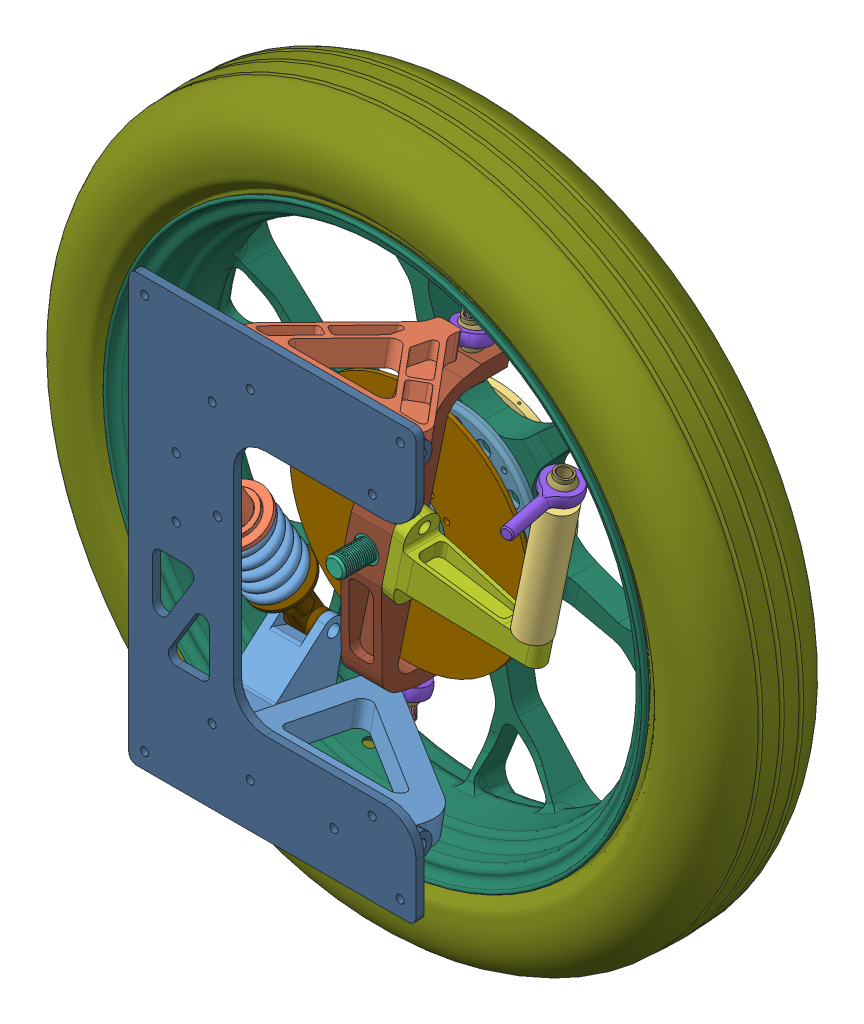
SolidWorks assembly Front Wheel Assembly, configuration Default. Lengths in mm.
Overall size (736.43 736.43 217.08).
26 component instances, 21 part files, 58 mates.
Components (placement in the parent):
- NewWishbone-1: NewWishbone [Default] at (-208.945 -92.3213 142.5637) x (1 0 0) z (0 0.196638 0.980476) size (183.89 64.96 127)
- NewWishboneTop-1: NewWishboneTop [Default] at (-199.42 176.9187 142.5637) x (1 0 0) z (0 0.196638 0.980476) size (146.05 19.05 127)
- Nut-1: Nut [Default] at (-174.02 47.8918 83.6508) x (0.981942 0.18918 0) z (0 0 1) size (130 130 15.86)
- SKF_6003-2Z.stp-1: SKF_6003-2Z.stp [Default] at (-174.02 47.8918 100.9457) x (0 0 -1) z (0.985702 -0.168499 0) size (10 35 35)
- SKF_6004-2Z.stp-1: SKF_6004-2Z.stp [Default] at (-174.02 47.8918 145.4457) x (0 0 -1) z (0.999998 -0.001926 0) size (12 42 42)
- Spindle_Light-1: Spindle_Light [Default] at (-174.0201 47.8918 152.4457) x (0 0 -1) z (0.979501 -0.20144 0) size (158.56 34 30)
- SteeringArmMount3-1: SteeringArmMount3 [Default] at (-158.1222 46.3873 152.4457) x (0 0 -1) z (0.979501 -0.20144 0) size (32.44 66.16 106.1)
- Swivel Ball Joint Rod End-1: Swivel Ball Joint Rod End [6960T231] at (-199.42 -82.9822 140.6908) x (-1 0 0) z (0 -0.980476 0.196638) size (28.57 68.26 9.89)
- BasicBrakeDisc-1: BasicBrakeDisc [Default] at (-174.02 47.8918 143.4457) x (0.999999 -0.001555 0) z (0 0 1) size (190.5 190.5 3.17)
- FrontSuspensionMountingPlate-1: FrontSuspensionMountingPlate [Default] at (-37.241 244.9178 278.0972) x (-1 0 0) z (0 0 -1) size (228.6 339.73 31.75)
- FrontSpindle-2: FrontSpindle [Default] at (-174.0201 47.8918 152.4457) x (1 0 0) z (0 0 1) size (83.21 247.02 73.5)
- Swivel Ball Joint Rod End-2: Swivel Ball Joint Rod End [6960T231] at (-148.62 186.2578 140.6908) x (-1 0 0) z (0 -0.980476 0.196638) size (28.57 68.26 9.89)
- Super-Swivel Ball Joint Ball End2-1: Super-Swivel Ball Joint Ball End2 [6960T231] at (-151.8803 182.5118 103.2437) x (0.985246 0 -0.171143) z (0 -1 0) size (20.64 20.64 22.23)
- Super-Swivel Ball Joint Ball End2-2: Super-Swivel Ball Joint Ball End2 [6960T231] at (-198.8916 -86.7282 102.97) x (0.999615 0 0.027738) z (0 -1 0) size (20.64 20.64 22.23)
- 91257A659_Zinc Yellow-Chromate Plated Hex Head Screw-2: 91257A659_Zinc Yellow-Chromate Plated Hex Head Screw [91257A659] at (-148.62 178.3843 122.0127) x (0 1 0) z (0.180681 0 0.983542) size (57.6 16.5 14.29)
- 91257A659_Zinc Yellow-Chromate Plated Hex Head Screw-3: 91257A659_Zinc Yellow-Chromate Plated Hex Head Screw [91257A659] at (-199.42 -82.6007 122.0127) x (0 -1 0) z (0.00058 0 1) size (57.6 16.5 14.29)
- Hub5-16-1: Hub5-16 [Default] at (-174.02 47.8918 125.0287) x (0.708206 0.706006 0) z (0.706006 -0.708206 0) size (130 85 130)
- rimmachined v13.2-1: rimmachined v13.2 [Default] at (-174.02 47.8918 128.7457) x (0 0 -1) z (-0.966188 -0.257837 0) size (93.59 431.57 431.57)
- Michelin Tire-1: Michelin Tire [Default] at (-174.02 47.8918 128.7457) x (0 0 -1) z (0.911284 -0.411779 0) size (101.13 556.61 556.61)
- Shock Absorber Rod_11-1: Shock Absorber Rod_11 [Default] at (-227.995 28.1327 206.2879) x (0.353558 0.474676 -0.806027) z (-0.935413 0.179413 -0.304654) size (6.35 19.21 6.35)
- Shock Anchor_11-1: Shock Anchor_11 [Default] at (-227.995 -29.8476 172.1429) x (1 0 0) z (0 0.50745 -0.861681) size (46 57.15 46)
- Shock Spring_11-1: Shock Spring_11 [Default] at (-228.2298 66.3963 229.124) x (1 0 0) z (0 0.50745 -0.861681) size (46 72.22 47.49)
- Shock Tube 1_11-1: Shock Tube 1_11 [Default] at (-227.995 95.9148 246.2053) x (1 0 0) z (0 -0.50745 0.861681) size (46 109.21 46)
- Standoff-1: Standoff [Default] at (-64.9504 35.3971 157.5898) x (0.972938 -0.20009 0.115567) z (-0.113198 0.02328 0.9933) size (25.4 101.6 25.4)
- Swivel Ball Joint Rod End-3: Swivel Ball Joint Rod End [6960T231] at (-38.9738 145.1479 176.3454) x (-0.964149 0.199376 0.175115) z (-0.202281 -0.979327 0.001288) size (28.57 68.26 9.89)
- Super-Swivel Ball Joint Ball End2-3: Super-Swivel Ball Joint Ball End2 [6960T231] at (-45.1475 146.3959 138.7715) x (0.967584 -0.198989 -0.155514) z (-0.20144 -0.979501 0) size (20.64 20.64 22.23)
Mates (geometry in assembly coordinates):
- Concentric2: concentric: cylinder of NewWishboneTop-1 through (-208.945 209.3578 255.8722) axis (1 0 0) radius 4.7625; cylinder of FrontSuspensionMountingPlate-1 through (-265.841 209.3578 255.8722) axis (1 0 0) radius 4.7625
- Distance1: distance = 0 mm: plane of NewWishboneTop-1 through (-189.895 195.5968 138.8178) normal (1 0 0); plane of FrontSuspensionMountingPlate-1 through (-189.895 244.9178 246.3472) normal (-1 0 0)
- Concentric3: concentric: cylinder of NewWishbone-1 through (-63.1563 -59.8822 255.8722) axis (-1 0 0) radius 4.7625; cylinder of FrontSuspensionMountingPlate-1 through (-265.841 -59.8822 255.8722) axis (1 0 0) radius 4.7625
- Concentric4: concentric: cylinder of NewWishboneTop-1 through (-148.62 193.7497 178.0469) axis (0 -0.196638 -0.980476) radius 4.7625; cylinder of Swivel Ball Joint Rod End-2 through (-148.62 186.2578 140.6908) axis (0 -0.196638 -0.980476) radius 4.7625
- Parallel1: parallel: plane of NewWishboneTop-1 through (-199.42 195.5968 138.8178) normal (0 0.980476 -0.196638); plane of Swivel Ball Joint Rod End-2 through (-134.3325 184.1773 107.1067) normal (0 0.980476 -0.196638)
- Coincident4: coincident: plane of NewWishboneTop-1 through (-199.42 195.5968 138.8178) normal (0 -0.196638 -0.980476); circle of Swivel Ball Joint Rod End-2
- Coincident5: coincident aligned: circle of NewWishbone-1; circle of Swivel Ball Joint Rod End-1
- Parallel2: parallel aligned: plane of NewWishbone-1 through (-208.945 -73.6432 138.8178) normal (0 0.980476 -0.196638); plane of Swivel Ball Joint Rod End-1 through (-185.1325 -85.0627 107.1067) normal (0 0.980476 -0.196638)
- Concentric5: concentric: sphere of Swivel Ball Joint Rod End-2; sphere of Super-Swivel Ball Joint Ball End2-1
- Concentric6: concentric: sphere of Swivel Ball Joint Rod End-1; sphere of Super-Swivel Ball Joint Ball End2-2
- Concentric8: concentric: circle of FrontSpindle-2; circle of Super-Swivel Ball Joint Ball End2-1
- Coincident11: coincident: plane of FrontSpindle-2 through (-132.4128 171.3993 180.9457) normal (0 1 0); plane of Super-Swivel Ball Joint Ball End2-1 through (-148.62 171.3993 122.0127) normal (0 -1 0)
- Concentric9: concentric: circle of FrontSpindle-2; circle of Super-Swivel Ball Joint Ball End2-2
- LimitAngle2: limit planar angle = 0.202828 rad aligned: plane of FrontSpindle-2 through (-183.2128 -75.6157 180.9457) normal (0.979501 -0.20144 0); plane of FrontSuspensionMountingPlate-1 through (-37.241 244.9178 271.7472) normal (1 0 0)
- Concentric10: concentric aligned: cylinder of FrontSpindle-2 through (-148.62 141.3993 122.0127) axis (0 1 0) radius 4.7625; cylinder of 91257A659_Zinc Yellow-Chromate Plated Hex Head Screw-2 through (-148.62 156.1593 122.0127) axis (0 1 0) radius 4.7625
- Coincident13: coincident anti-aligned: plane of FrontSpindle-2 through (-174.02 156.1593 107.4457) normal (0 -1 0); plane of 91257A659_Zinc Yellow-Chromate Plated Hex Head Screw-2 through (-151.3859 156.1593 129.7841) normal (0 1 0)
- Concentric11: concentric aligned: cylinder of FrontSpindle-2 through (-199.42 -45.6157 122.0127) axis (0 -1 0) radius 4.7625; cylinder of 91257A659_Zinc Yellow-Chromate Plated Hex Head Screw-3 through (-199.42 -60.3757 122.0127) axis (0 -1 0) radius 4.7625
- Coincident14: coincident anti-aligned: plane of FrontSpindle-2 through (-174.02 -60.3757 107.4457) normal (0 1 0); plane of 91257A659_Zinc Yellow-Chromate Plated Hex Head Screw-3 through (-195.2915 -60.3757 129.154) normal (0 -1 0)
- Concentric12: concentric aligned: cylinder of Spindle_Light-1 through (-174.02 47.8918 65.9457) axis (0 0 -1) radius 10; cylinder of FrontSpindle-2 through (-174.0201 47.8918 180.9457) axis (0 0 -1) radius 10
- Parallel6: parallel aligned: plane of Spindle_Light-1 through (-192.5231 32.3847 165.9457) normal (-0.979501 0.20144 0); plane of FrontSpindle-2 through (-215.6273 -75.6157 180.9457) normal (-0.979501 0.20144 0)
- Coincident17: coincident anti-aligned: plane of Spindle_Light-1 through (-172.0057 57.6868 152.4457) normal (0 0 1); plane of FrontSpindle-2 through (-174.0201 47.8918 152.4457) normal (0 0 -1)
- Concentric14: concentric aligned: cylinder of SKF_6004-2Z.stp-1 through (-174.02 47.8918 95.4457) axis (0 0 -1) radius 10; cylinder of Spindle_Light-1 through (-174.02 47.8918 65.9457) axis (0 0 -1) radius 10
- Coincident18: coincident: plane of SKF_6004-2Z.stp-1 through (-173.9941 61.3718 145.4457) normal (0 0 1); plane of Spindle_Light-1 through (-171.6028 59.6458 145.4457) normal (0 0 -1)
- Concentric15: concentric aligned: cylinder of SKF_6003-2Z.stp-1 through (-174.02 47.8918 50.9457) axis (0 0 -1) radius 8.5; cylinder of Spindle_Light-1 through (-174.02 47.8918 65.9457) axis (0 0 -1) radius 8.5
- Coincident19: coincident: plane of SKF_6004-2Z.stp-1 through (-173.9842 66.4868 133.4457) normal (0 0 -1); plane of Hub5-16-1 through (-160.5641 61.3059 136.4457) normal (0 0 1)
- Concentric16: concentric anti-aligned: cylinder of SKF_6003-2Z.stp-1 through (-174.02 47.8918 50.9457) axis (0 0 -1) radius 17.5; cylinder of Hub5-16-1 through (-174.0201 47.8918 1051.0565) axis (0 0 1) radius 17.5
- Coincident20: coincident anti-aligned: plane of SKF_6003-2Z.stp-1 through (-171.1219 64.8459 100.9457) normal (0 0 1); plane of Hub5-16-1 through (-163.0429 58.8349 100.9457) normal (0 0 -1)
- Concentric17: concentric anti-aligned: cylinder of Hub5-16-1 through (-174.0201 47.8918 1051.0565) axis (0 0 1) radius 47; cylinder of rimmachined v13.2-1 through (-174.02 47.8918 119.6457) axis (0 0 -1) radius 47.005
- Concentric18: concentric aligned: circle of Nut-1; circle of Hub-1
- Concentric22: concentric anti-aligned: cylinder of BasicBrakeDisc-1 through (-174.02 47.8918 146.6207) axis (0 0 -1) radius 28.956; cylinder of Hub5-16-1 through (-174.0201 47.8918 1051.0565) axis (0 0 1) radius 29
- Coincident23: coincident anti-aligned: plane of BasicBrakeDisc-1 through (-174.02 47.8918 143.4457) normal (0 0 -1); plane of Hub5-16-1 through (-153.4821 68.366 143.4457) normal (0 0 1)
- Concentric25: concentric anti-aligned: cylinder of BasicBrakeDisc-1 through (-203.4384 64.9376 146.6207) axis (0 0 -1) radius 2.497; cylinder of Hub5-16-1 through (-203.4384 64.9376 133.4457) axis (0 0 1) radius 2
- Coincident24: coincident anti-aligned: plane of Hub5-16-1 through (-140.7344 81.0741 106.4457) normal (0 0 -1); plane of rimmachined v13.2-1 through (-163.7066 9.2443 106.4457) normal (0 0 1)
- Tangent6: tangent anti-aligned: cylinder of Hub5-16-1 through (-188.9444 103.9388 109.9457) axis (0 0 -1) radius 3.9688; plane of rimmachined v13.2-1 through (-184.4652 102.5466 102.1457) normal (-0.966188 -0.257837 0)
- Concentric31: concentric anti-aligned: circle of Nut-1; circle of rimmachined v13.2-1
- Coincident25: coincident anti-aligned: plane of Nut-1 through (-139.6521 54.5131 83.6508) normal (0 0 1); plane of rimmachined v13.2-1 through (-153.6044 -28.6115 83.6508) normal (0 0 -1)
- Concentric32: concentric aligned: cylinder of rimmachined v13.2-1 through (-174.0201 47.8918 214.2549) axis (0 0 1) radius 192.7898; cylinder of Michelin Tire-1 through (-174.0201 47.8918 231.4686) axis (0 0 1) radius 203
- Coincident26: coincident aligned: plane of rimmachined v13.2-1 through (-174.02 47.8918 128.7457) normal (0 0 -1); plane of Michelin Tire-1 through (-174.02 47.8918 128.7457) normal (0 0 -1)
- Coincident27: coincident anti-aligned: plane of SteeringArmMount3-1 through (-158.1222 46.3873 152.4457) normal (-0.979501 0.20144 0); plane of FrontSpindle-2 through (-183.2128 -75.6157 180.9457) normal (0.979501 -0.20144 0)
- Coincident28: coincident: point of SteeringArmMount3-1; point of FrontSpindle-2
- Concentric34: concentric: cylinder of Shock Absorber Rod_11-1 through (-227.995 11.5764 196.5377) axis (0 0.861681 0.50745) radius 3.175; cylinder of Shock Tube 1_11-1 through (-227.995 50.0194 219.1771) axis (0 -0.861681 -0.50745) radius 3.175
- Coincident29: coincident anti-aligned: plane of Shock Anchor_11-1 through (-227.995 11.19 196.3102) normal (0 0.861681 0.50745); plane of Shock Spring_11-1 through (-228.2298 11.0578 196.5347) normal (0 -0.861681 -0.50745)
- Lock1: lock: unknown of Shock Anchor_11-1; unknown of Shock Spring_11-1
- Concentric35: concentric: cylinder of Shock Anchor_11-1 through (-227.995 -18.9042 178.5875) axis (0 -0.861681 -0.50745) radius 8.6614; cylinder of Shock Tube 1_11-1 through (-227.995 66.9149 229.127) axis (0 0.861681 0.50745) radius 11.43
- Concentric36: concentric: cylinder of NewWishbone-1 through (-247.045 -29.8476 172.1429) axis (1 0 0) radius 4.7625; cylinder of Shock Anchor_11-1 through (-221.645 -29.8476 172.1429) axis (-1 0 0) radius 5
- Coincident31: coincident: plane of NewWishbone-1 through (-240.06 -92.3213 142.5637) normal (1 0 0); plane of Shock Anchor_11-1 through (-240.06 -29.8476 172.1429) normal (-1 0 0)
- Concentric37: concentric: cylinder of FrontSuspensionMountingPlate-1 through (-265.841 112.3298 255.8722) axis (1 0 0) radius 4.7625; cylinder of Shock Tube 1_11-1 through (-215.93 112.3298 255.8722) axis (-1 0 0) radius 4.9166
- Coincident32: coincident: circle of Shock Absorber Rod_11-1; circle of Shock Tube 1_11-1
- Coincident33: coincident anti-aligned: line of SteeringArmMount3-1 through (-153.6771 68.0019 180.9457) axis (-0.20144 -0.979501 0); line of FrontSpindle-2 through (-161.9486 27.7818 180.9457) axis (0.20144 0.979501 0)
- Concentric38: concentric anti-aligned: cylinder of SteeringArmMount3-1 through (-72.6253 -1.9219 157.5898) axis (0.20144 0.979501 0) radius 4.7625; cylinder of Standoff-1 through (-44.4841 134.9144 157.5898) axis (-0.20144 -0.979501 0) radius 4.7625
- Distance4: distance = 0 mm anti-aligned: plane of Standoff-1 through (-64.9504 35.3971 157.5898) normal (-0.20144 -0.979501 0); plane of SteeringArmMount3-1 through (-156.51 54.2268 148.5086) normal (0.20144 0.979501 0)
- Concentric40: concentric aligned: cylinder of Standoff-1 through (-44.4841 134.9144 157.5898) axis (-0.20144 -0.979501 0) radius 4.7625; cylinder of Super-Swivel Ball Joint Ball End2-3 through (-40.167 155.9063 157.5898) axis (-0.20144 -0.979501 0) radius 4.7625
- Coincident35: coincident anti-aligned: plane of Standoff-1 through (-44.4841 134.9144 157.5898) normal (0.20144 0.979501 0); plane of Super-Swivel Ball Joint Ball End2-3 through (-44.4841 134.9144 157.5898) normal (-0.20144 -0.979501 0)
- Concentric41: concentric: sphere of Swivel Ball Joint Rod End-3; sphere of Super-Swivel Ball Joint Ball End2-3
- Lock2: lock: unknown of BasicBrakeDisc-1; unknown of FrontSpindle-2
- Parallel16: parallel: plane of NewWishbone-1 through (-208.945 -73.6432 138.8178) normal (0 0.980476 -0.196638); plane of NewWishboneTop-1 through (-199.42 176.9187 142.5637) normal (0 -0.980476 0.196638)
- LimitAngle6: limit planar angle = 0.001548 rad aligned: plane of Swivel Ball Joint Rod End-3 through (-30.001 147.9086 141.0152) normal (0.202281 0.979327 -0.001288); plane of Standoff-1 through (-44.4841 134.9144 157.5898) normal (0.20144 0.979501 0)
- Distance5: distance = 64.67 mm: plane of Shock Tube 1_11-1 through (-227.995 66.9149 229.127) normal (0 -0.861681 -0.50745); plane of Shock Anchor_11-1 through (-227.995 11.19 196.3102) normal (0 0.861681 0.50745)
